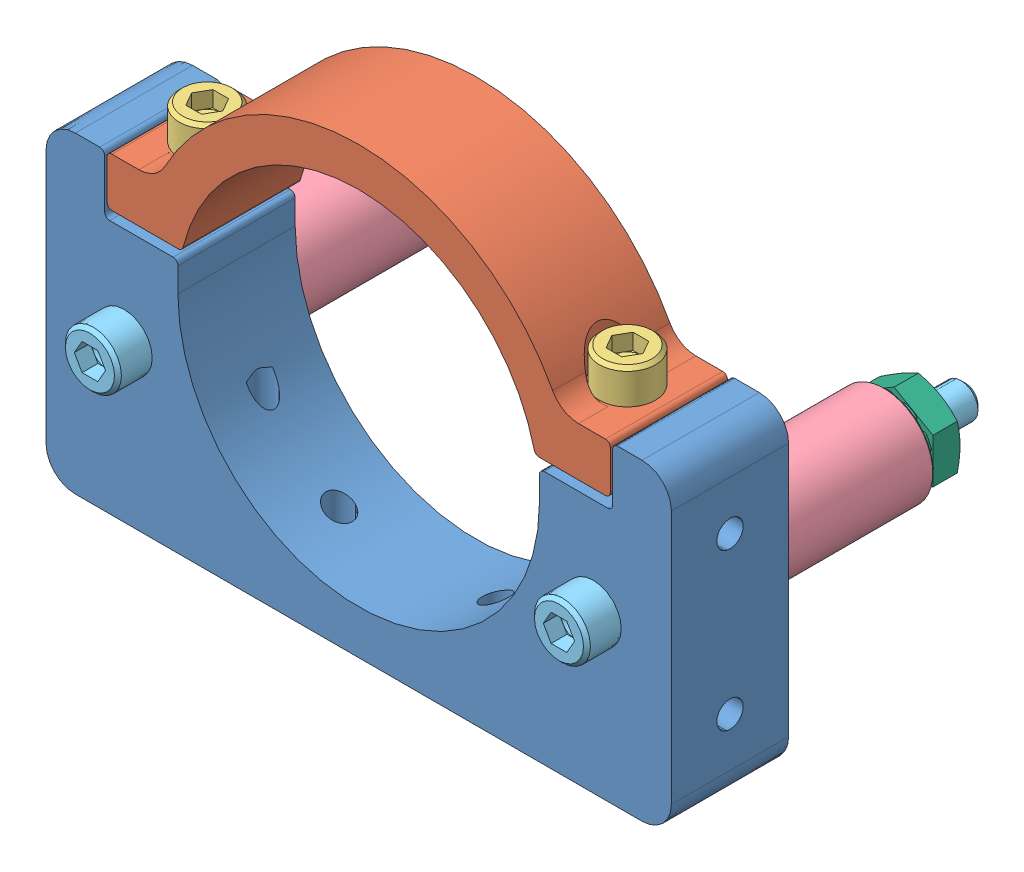
SolidWorks assembly Example Motor Mount, configuration Default. Lengths in mm.
Overall size (64 45.5 41.61).
10 component instances, 6 part files, 0 mates.
Components (placement in the parent):
- Tetrix Motor Mount A-1: Tetrix Motor Mount A [Default] at origin size (64 32 12)
- Tetrix Motor Mount B-1: Tetrix Motor Mount B [Default] at (0 1 0) size (51.5 18.5 12)
- Tetrix Screw Large B-1: Tetrix Screw Large B [Default] at (-21.5 6 0) size (5.74 16.21 5.74)
- Tetrix Screw Large B-2: Tetrix Screw Large B [Default] at (21.5 6 0) size (5.74 16.21 5.74)
- Tetrix Motor Mount Spacer-1: Tetrix Motor Mount Spacer [Default] at (24 -10 -15) size (10 10 18)
- Tetrix Motor Mount Spacer-2: Tetrix Motor Mount Spacer [Default] at (-24 -10 -15) size (10 10 18)
- Tetrix Screw Long B-1: Tetrix Screw Long B [Default] at (-24 -10 6) x (-1 0 0) z (0 1 0) size (5.74 41.61 5.74)
- Tetrix Screw Long B-2: Tetrix Screw Long B [Default] at (24 -10 6) x (-1 0 0) z (0 1 0) size (5.74 41.61 5.74)
- Tetrix Nut B-1: Tetrix Nut B [Default] at (24 -10 -26.1828) x (1 0 0) z (0 1 0) size (8.75 3.61 9.17)
- Tetrix Nut B-2: Tetrix Nut B [Default] at (-24 -10 -26.1828) x (1 0 0) z (0 1 0) size (8.75 3.61 9.17)
